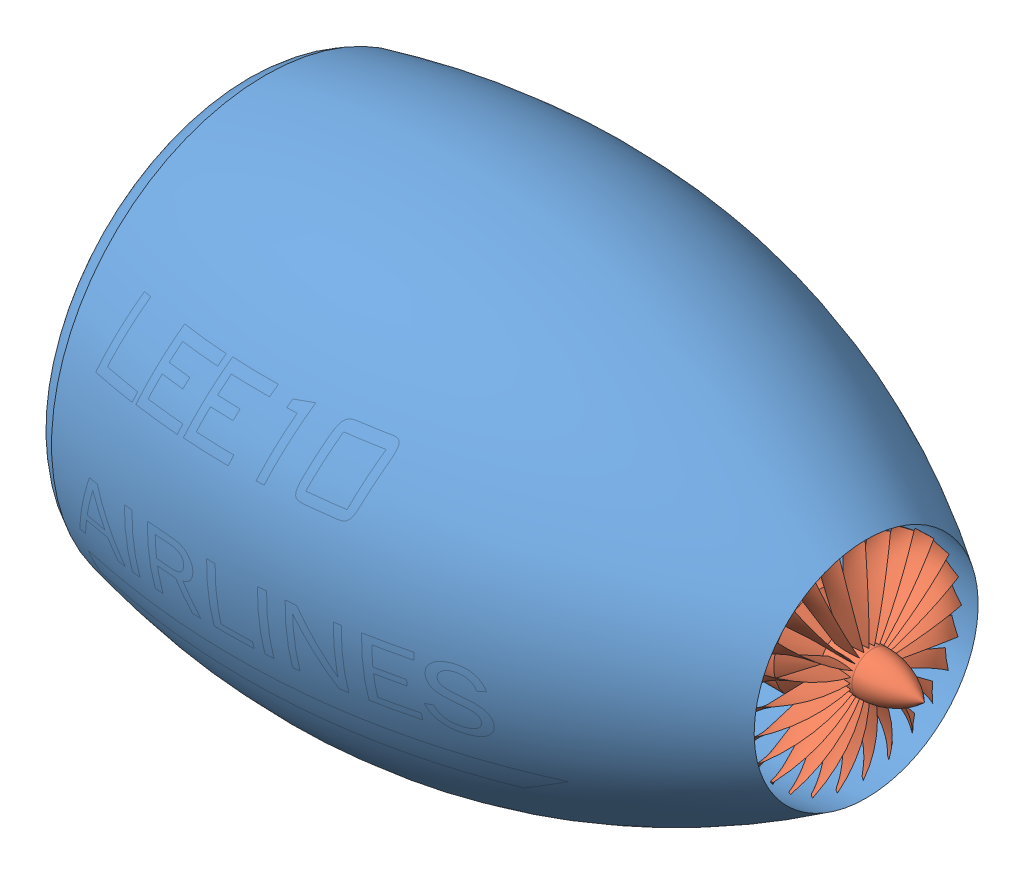
SolidWorks assembly PLANE propeller assembly, configuration Default. Lengths in mm.
Overall size (778 487.08 487.08).
3 component instances, 3 part files, 5 mates.
Components (placement in the parent):
- Part3(PROPELLER-1: Part3(PROPELLER [Default] at (-89.8818 359.8262 434.9586) size (597.59 487.08 487.08)
- Part2(propeller)-1: Part2(propeller) [Default] at (-103.6382 359.8262 434.9586) x (1 0 0) z (0 0.952047 0.30595) size (650 200.07 200.43)
- plane turbine-1: plane turbine [Default] at (-231.6382 359.8262 434.9586) x (0 0.30595 -0.952047) z (-1 0 0) size (350.4 350.77 184.33)
Mates (geometry in assembly coordinates):
- Concentric1: concentric aligned: cylinder of Part2(propeller)-1 through (496.3618 359.8262 434.9586) axis (1 0 0) radius 20; cylinder of plane turbine-1 through (-103.6382 359.8262 434.9586) axis (1 0 0) radius 20
- Coincident1: coincident anti-aligned: plane of Part2(propeller)-1 through (-103.6382 359.8262 434.9586) normal (-1 0 0); plane of plane turbine-1 through (-103.6382 359.8262 434.9586) normal (1 0 0)
- Concentric2: concentric anti-aligned: cylinder of Part3(PROPELLER-1 through (-89.8818 359.8262 434.9586) axis (-1 0 0) radius 190; cylinder of Part2(propeller)-1 through (496.3618 359.8262 434.9586) axis (1 0 0) radius 42.7405
- Coincident6: coincident aligned: circle of Part3(PROPELLER-1; plane of Part2(propeller)-1 through (-2.9083 340.7852 428.8396) normal (-1 0 0)
- Coincident7: coincident anti-aligned: plane of Part2(propeller)-1 through (-103.6382 359.8262 434.9586) normal (0 0.952047 0.30595); plane of plane turbine-1 through (-231.6382 359.8262 434.9586) normal (0 -0.952047 -0.30595)
